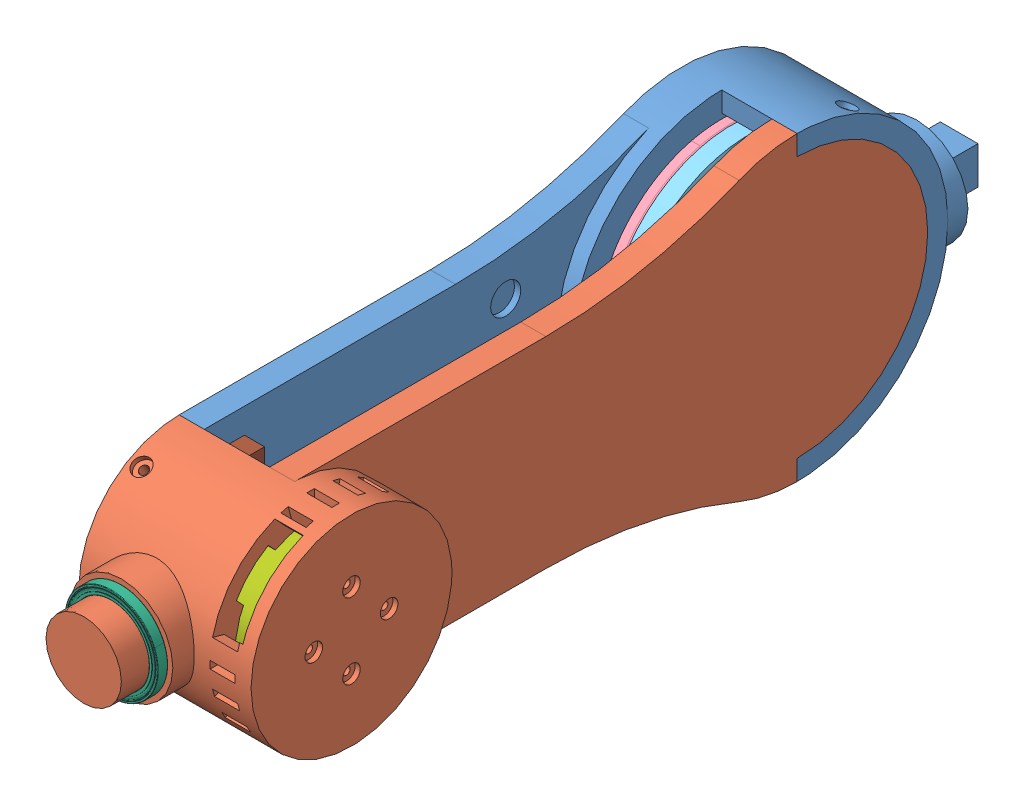
SolidWorks assembly shoulder assembly mirrored, configuration Default. Lengths in mm.
Overall size (73.24 150.9 348.5).
12 component instances, 11 part files, 24 mates.
Components (placement in the parent):
- body hip mirrored-1: body hip mirrored [Default] at (77.5957 180.2345 175.6749) size (46 120 315)
- body hip cover mirrored-1: body hip cover mirrored [Default] at (113.5957 180.2345 175.6749) size (68.6 120 315.5)
- AXK_80105___AS_80105___AS_80105-1: AXK_80105___AS_80105___AS_80105 [Default] at (76.5957 180.2345 175.6749) x (1 0 0) z (0 0.11129 0.993788) size (6 105 105)
- W_61816_2Z-1: W_61816_2Z [Default] at (87.5957 180.2345 175.6749) x (1 0 0) z (0 0.970343 0.241732) size (10 124.5 124.5)
- shoulder GT2 120-1: shoulder GT2 120 [Default] at (100.3957 180.2345 175.6749) x (0 -0.340984 -0.940069) z (0 -0.940069 0.340984) size (86 20 86)
- W_61706_2RZ-1: W_61706_2RZ [Default] at (113.5957 180.2345 175.6749) size (4 46.12 46.12)
- MAD5008IPE-1: MAD5008IPE [Default] at (141.1957 180.2345 375.6749) x (0 1 0) z (0 0 1) size (56 29.3 56)
- GT2 15 Teeth motor-1: GT2 15 Teeth motor [Default] at (113.7803 180.2345 375.6749) x (0 1 0) z (0 0 1) size (24 30 24)
- W_61706_2RZ-2: W_61706_2RZ [Default] at (103.0957 180.2345 424.1749) x (0 0 1) z (0.923728 0.383049 0) size (4 46.12 46.12)
- W_617_8-1: W_617_8 [Default] at (85.0957 180.2345 375.6749) size (2.5 14.75 14.75)
- encoder-1: encoder [Default] at (93.8257 180.2345 375.6749) x (0 -0.999972 0.00746) z (-1 0 0) size (28.79 43.54 9.21)
- hip joint encoder holder-1: hip joint encoder holder [Default] at (101.5957 180.2345 375.6749) x (0 -1 0) z (0 0 -1) size (80 8 46)
Mates (geometry in assembly coordinates):
- Concentric1: concentric: cylinder of body hip mirrored-1 through (79.5957 180.2345 175.6749) axis (-1 0 0) radius 52.5; cylinder of AXK_80105___AS_80105___AS_80105-1 through (78.1957 180.2345 175.6749) axis (-1 0 0) radius 52.5
- Coincident1: coincident: plane of body hip mirrored-1 through (79.5957 180.2345 175.6749) normal (-1 0 0); plane of AXK_80105___AS_80105___AS_80105-1 through (79.5957 219.986 171.2233) normal (1 0 0)
- Concentric2: concentric: cylinder of body hip mirrored-1 through (93.5957 180.2345 175.6749) axis (-1 0 0) radius 50; cylinder of W_61816_2Z-1 through (137.5957 180.2345 175.6749) axis (1 0 0) radius 50
- Coincident2: coincident: plane of body hip mirrored-1 through (87.5957 180.2345 175.6749) normal (1 0 0); plane of W_61816_2Z-1 through (87.5957 190.6483 133.8726) normal (-1 0 0)
- Concentric3: concentric: cylinder of W_61816_2Z-1 through (137.5957 180.2345 175.6749) axis (1 0 0) radius 40; cylinder of shoulder GT2 120-1 through (101.3957 180.2345 175.6749) axis (1 0 0) radius 43
- Coincident3: coincident: plane of W_61816_2Z-1 through (97.5957 190.0488 136.279) normal (1 0 0); plane of shoulder GT2 120-1 through (97.5957 180.2345 175.6749) normal (-1 0 0)
- Concentric4: concentric: cylinder of shoulder GT2 120-1 through (117.5957 180.2345 175.6749) axis (-1 0 0) radius 15; cylinder of W_61706_2RZ-1 through (163.5957 180.2345 175.6749) axis (1 0 0) radius 18.5
- Coincident4: coincident: plane of shoulder GT2 120-1 through (113.5957 180.2345 175.6749) normal (1 0 0); plane of W_61706_2RZ-1 through (113.5957 196.3678 175.6749) normal (-1 0 0)
- Concentric5: concentric: cylinder of MAD5008IPE-1 through (115.3957 180.2345 375.6749) axis (1 0 0) radius 28; cylinder of GT2 15 Teeth motor-1 through (113.7803 180.2345 375.6749) axis (1 0 0) radius 12
- Coincident5: coincident: plane of MAD5008IPE-1 through (115.3957 180.2345 375.6749) normal (-1 0 0); plane of GT2 15 Teeth motor-1 through (115.3957 168.2345 375.6749) normal (1 0 0)
- Concentric7: concentric: cylinder of body hip cover mirrored-1 through (113.5957 180.2345 375.6749) axis (1 0 0) radius 30; cylinder of MAD5008IPE-1 through (115.3957 180.2345 375.6749) axis (1 0 0) radius 28
- Coincident6: coincident: plane of body hip cover mirrored-1 through (141.1957 180.2345 375.6749) normal (-1 0 0); plane of MAD5008IPE-1 through (141.1957 180.2345 375.6749) normal (1 0 0)
- Concentric8: concentric: cylinder of body hip mirrored-1 through (87.5957 180.2345 175.6749) axis (-1 0 0) radius 60; cylinder of body hip cover mirrored-1 through (123.5957 180.2345 175.6749) axis (-1 0 0) radius 60
- Concentric9: concentric: cylinder of body hip cover mirrored-1 through (113.5957 180.2345 375.6749) axis (1 0 0) radius 30; cylinder of body hip mirrored-1 through (77.5957 180.2345 375.6749) axis (1 0 0) radius 30
- Concentric10: concentric: cylinder of body hip cover mirrored-1 through (103.0957 180.2345 439.1749) axis (0 0 -1) radius 15; cylinder of W_61706_2RZ-2 through (103.0957 180.2345 474.1749) axis (0 0 1) radius 15
- Coincident8: coincident: plane of body hip cover mirrored-1 through (103.0957 180.2345 424.1749) normal (0 0 1); plane of W_61706_2RZ-2 through (109.2756 165.3317 424.1749) normal (0 0 -1)
- Coincident11: coincident: plane of body hip mirrored-1 through (123.5957 180.2345 175.6749) normal (1 0 0); plane of body hip cover mirrored-1 through (123.5957 180.2345 175.6749) normal (1 0 0)
- Coincident12: coincident: plane of body hip mirrored-1 through (85.0957 180.2345 375.6749) normal (1 0 0); plane of W_617_8-1 through (85.0957 184.7295 375.6749) normal (-1 0 0)
- Concentric11: concentric: cylinder of GT2 15 Teeth motor-1 through (113.7094 180.2345 375.6749) axis (-1 0 0) radius 4; cylinder of W_617_8-1 through (135.0957 180.2345 375.6749) axis (1 0 0) radius 4
- Concentric12: concentric: cylinder of GT2 15 Teeth motor-1 through (113.7094 180.2345 375.6749) axis (-1 0 0) radius 4; cylinder of encoder-1 through (97.5957 180.2345 375.6749) axis (-1 0 0) radius 6.3
- Concentric13: concentric: cylinder of GT2 15 Teeth motor-1 through (113.7094 180.2345 375.6749) axis (-1 0 0) radius 4; cylinder of hip joint encoder holder-1 through (97.5957 180.2345 375.6749) axis (1 0 0) radius 4.5
- Coincident13: coincident: plane of body hip cover mirrored-1 through (82.5957 150.2345 375.6749) normal (0 0 -1); plane of hip joint encoder holder-1 through (105.5957 164.2345 375.6749) normal (0 0 1)
- Concentric14: concentric: cylinder of body hip cover mirrored-1 through (101.5957 145.2345 375.6749) axis (0 0 -1) radius 2.05; cylinder of hip joint encoder holder-1 through (101.5957 145.2345 369.6749) axis (0 0 -1) radius 1.7
- Coincident14: coincident: plane of encoder-1 through (97.5957 194.4122 347.5211) normal (1 0 0); plane of hip joint encoder holder-1 through (97.5957 180.2345 375.6749) normal (-1 0 0)
